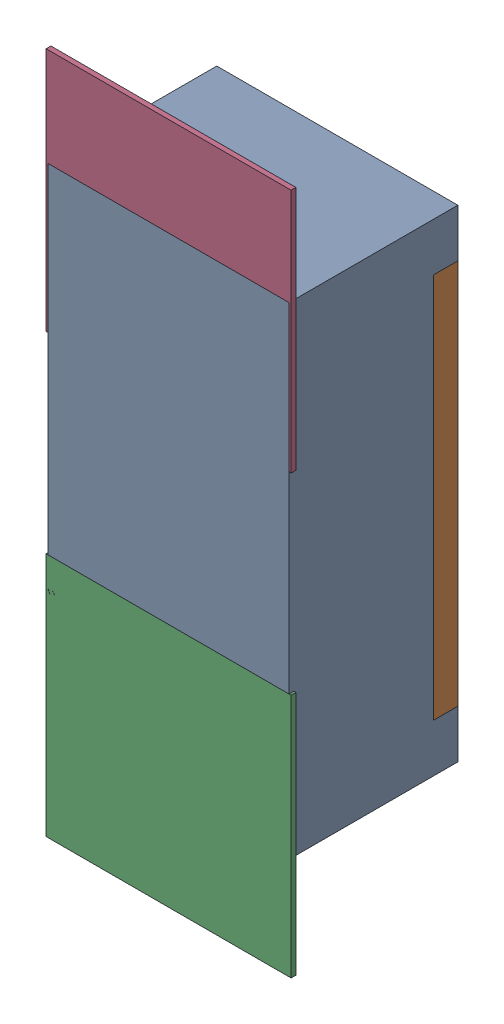
SolidWorks assembly R126, configuration Défaut. Lengths in mm.
Overall size (0.51 1.42 0.35).
5 component instances, 2 part files, 0 mates.
Components (placement in the parent):
- R0402-1: R0402 [Défaut] at (17.9831 -6.2358 -2.0818) x (0 1 0) z (0 0 -1) size (1 0.5 0.35)
- 6504207776-1: 6504207776 [Défaut] at (17.9832 -6.6929 -2.0918) size (0.51 0.51 0.01)
  - Extruded-1: Extruded [Défaut] at origin size (0.51 0.51 0.01)
- 6504207776-2: 6504207776 [Défaut] at (17.9832 -5.7858 -2.0918) size (0.51 0.51 0.01)
  - Extruded-1: Extruded [Défaut] at origin size (0.51 0.51 0.01)
